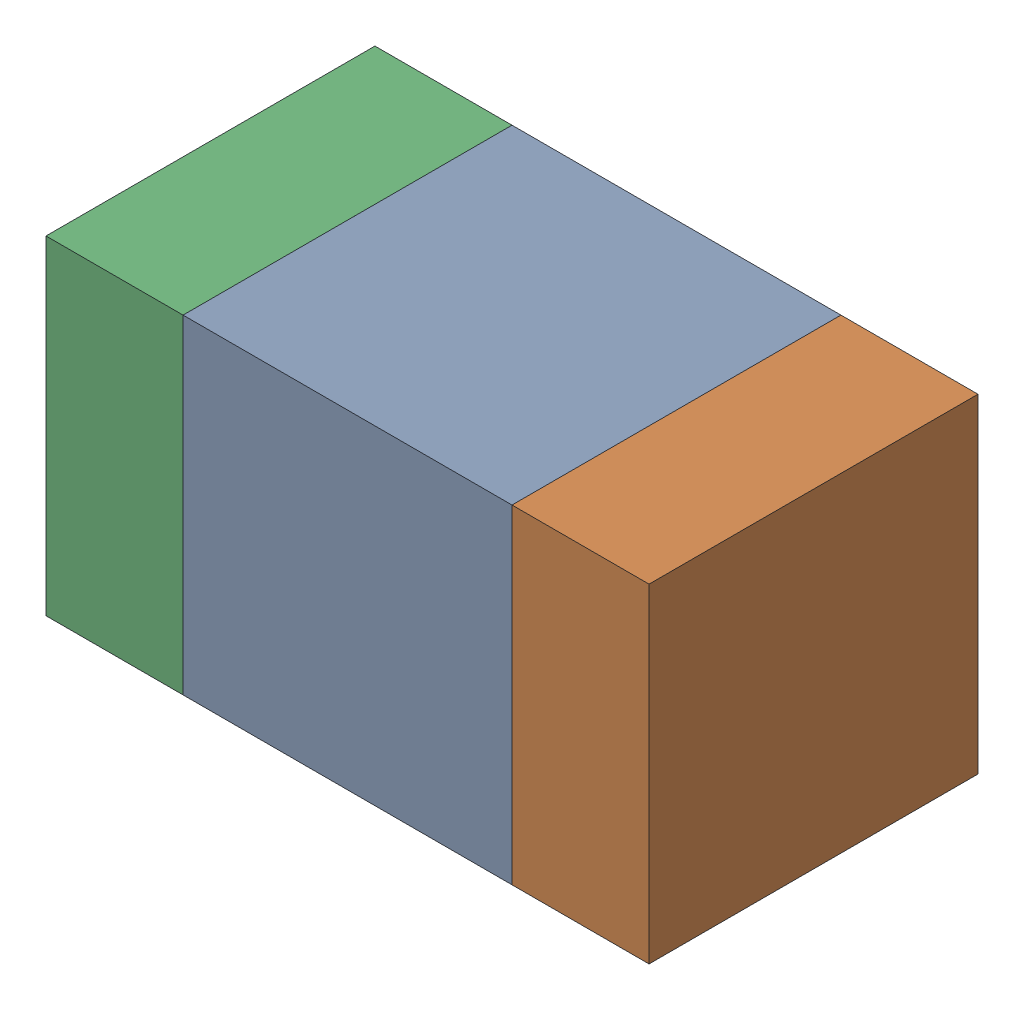
SolidWorks assembly C302_1PCB, configuration Default. Lengths in mm.
Overall size (1.1 0.6 0.6).
6 component instances, 2 part files, 0 mates.
Components (placement in the parent):
- 761606048-1: 761606048 [Default] at (145.3 107 0) size (0.6 0.6 0.6)
  - Extruded_9-1: Extruded_9 [Default] at origin size (0.6 0.6 0.6)
- 854785160-1: 854785160 [Default] at (145.725 107 0) size (0.25 0.6 0.6)
  - Extruded_19-1: Extruded_19 [Default] at origin size (0.25 0.6 0.6)
- 854785160-2: 854785160 [Default] at (144.875 107 0) size (0.25 0.6 0.6)
  - Extruded_19-1: Extruded_19 [Default] at origin size (0.25 0.6 0.6)
